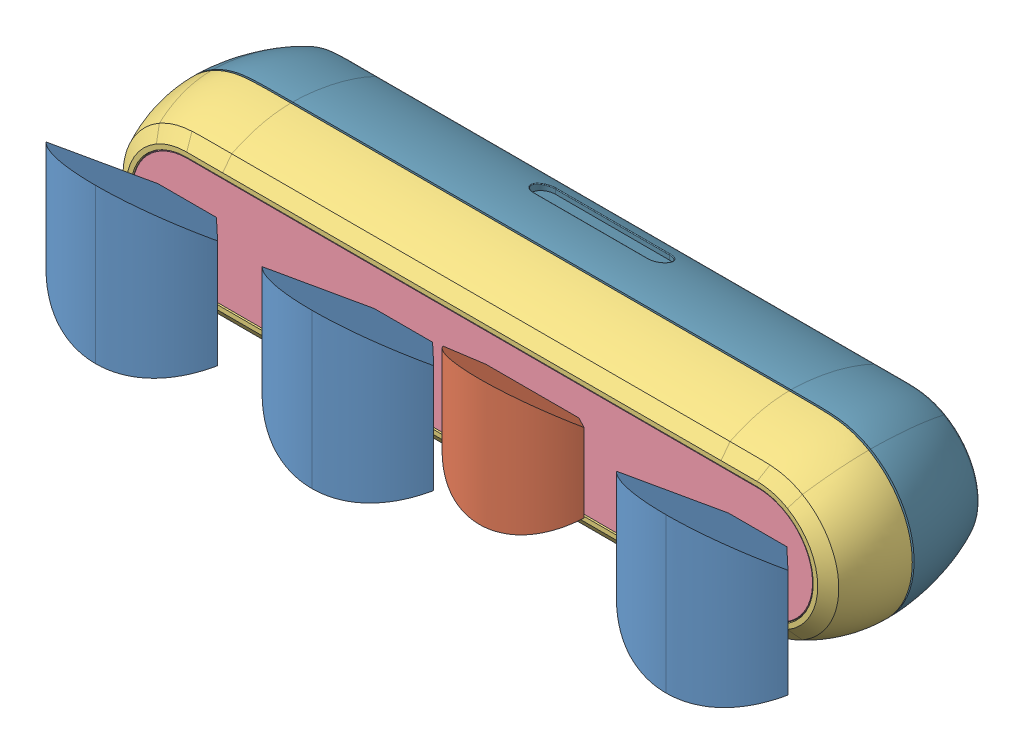
SolidWorks assembly Intel_RealSense_D455_CAD_external_v2, configuration Default. Lengths in mm.
Overall size (124.01 29.03 41.17).
49 component instances, 21 part files, 0 mates.
Components (placement in the parent):
- MD0645501_ASM_12_ASM-1: MD0645501_ASM_12_ASM [MD0645501_ASM_12_ASM] at origin size (124.01 29.03 26.02)
  - AM0600131_ASM_2_ASM-1: AM0600131_ASM_2_ASM [AM0600131_ASM_2_ASM] at origin size (124 29.01 12.31)
    - MEC060312_ASM_4_ASM-1: MEC060312_ASM_4_ASM [MEC060312_ASM_4_ASM] at origin size (111.1 18.8 0.79)
      - DS5_0390_FOAM_FRONT_D455_3-1: DS5_0390_FOAM_FRONT_D455_3 [DS5_0390_FOAM_FRONT_D455_3] at origin size (111.1 18.8 0.76)
      - DS5_0390_ADHESIVE_D455_2-1: DS5_0390_ADHESIVE_D455_2 [DS5_0390_ADHESIVE_D455_2] at (0 0 -1.32) size (111.1 18.8 0.03)
    - MEC060311_6-1: MEC060311_6 [MEC060311_6] at origin size (124 29.01 12.31)
  - AM0600132_ASM_3_ASM-1: AM0600132_ASM_3_ASM [AM0600132_ASM_3_ASM] at origin size (113.48 18.48 0.7)
    - MEC060313_2-1: MEC060313_2 [MEC060313_2] at origin size (113.48 18.48 0.55)
    - MASK_LENS_COVER_D455_3-1: MASK_LENS_COVER_D455_3 [MASK_LENS_COVER_D455_3] at origin size (113.28 18.28 0.03)
    - MEC060314_5-1: MEC060314_5 [MEC060314_5] at origin size (112.88 17.88 0.13)
  - AM0600135_ASM_3_ASM-1: AM0600135_ASM_3_ASM [AM0600135_ASM_3_ASM] at origin size (120.07 27.45 12.56)
    - MEC060318_11-1: MEC060318_11 [MEC060318_11] at origin size (120.07 27.45 12.56)
    - MEC060319_2-1: MEC060319_2 [MEC060319_2] at (35.3 0 -12.295) size (1.48 1.48 3)
    - MEC060319_2-2: MEC060319_2 [MEC060319_2] at (-38.5 0 -12.295) size (1.48 1.48 3)
  - MEC060309_ASM_5_ASM-1: MEC060309_ASM_5_ASM [MEC060309_ASM_5_ASM] at origin size (108.7 16.4 1.68)
    - DS5_0390_LABEL_FRONT_MOD_D455_5-1: DS5_0390_LABEL_FRONT_MOD_D455_5 [DS5_0390_LABEL_FRONT_MOD_D455_5] at origin size (108.7 16.4 1.68)
    - DS5_0390_LABEL_FRONT_ADH_D455_3-1: DS5_0390_LABEL_FRONT_ADH_D455_3 [DS5_0390_LABEL_FRONT_ADH_D455_3] at origin size (108.7 16.4 0.06)
  - AS0605401_ASM_4_ASM-1: AS0605401_ASM_4_ASM [AS0605401_ASM_4_ASM] at origin size (8.74 8.48 3.97)
    - 10137062C_1_ASM_2_ASM-1: 10137062C_1_ASM_2_ASM [10137062C_1_ASM_2_ASM] at (-37.01 -9 -21.3) x (1 0 0) z (0 -1 0) size (8.74 3.97 8.48)
      - 10137062C_1_1_1-1: 10137062C_1_1_1 [10137062C_1_1_1] at origin size (8.74 3.97 8.48)
  - AM0600133_ASM_2_ASM-1: AM0600133_ASM_2_ASM [AM0600133_ASM_2_ASM] at origin size (124.01 29.03 14.45)
    - FAS000227_ASM_2_ASM-1: FAS000227_ASM_2_ASM [FAS000227_ASM_2_ASM] at (-47.5 0 -25.4937) x (-1 0 0) z (0 1 0) size (5.62 3.92 5.68)
      - 91732A649_ASM_1_ASM-1: 91732A649_ASM_1_ASM [91732A649_ASM_1_ASM] at origin size (5.62 3.92 5.68)
        - SWEEP1_1-1: SWEEP1_1 [SWEEP1_1] at origin size (5.62 3.92 5.68)
    - FAS000227_ASM_2_ASM-2: FAS000227_ASM_2_ASM [FAS000227_ASM_2_ASM] at (47.5 0 -25.4937) x (-1 0 0) z (0 1 0) size (5.62 3.92 5.68)
      - 91732A649_ASM_1_ASM-1: 91732A649_ASM_1_ASM [91732A649_ASM_1_ASM] at origin size (5.62 3.92 5.68)
        - SWEEP1_1-1: SWEEP1_1 [SWEEP1_1] at origin size (5.62 3.92 5.68)
    - FAS000226_ASM_2_ASM-1: FAS000226_ASM_2_ASM [FAS000226_ASM_2_ASM] at (-44.51 -14.325 -19.85) size (2.7 1.95 2.7)
      - 91732A181_ASM_1_ASM-1: 91732A181_ASM_1_ASM [91732A181_ASM_1_ASM] at origin size (2.7 1.95 2.7)
        - SWEEP1_1_2_3_1-1: SWEEP1_1_2_3_1 [SWEEP1_1_2_3_1] at origin size (2.7 1.95 2.7)
    - FAS000226_ASM_2_ASM-2: FAS000226_ASM_2_ASM [FAS000226_ASM_2_ASM] at (-29.51 -14.325 -19.85) size (2.7 1.95 2.7)
      - 91732A181_ASM_1_ASM-1: 91732A181_ASM_1_ASM [91732A181_ASM_1_ASM] at origin size (2.7 1.95 2.7)
        - SWEEP1_1_2_3_1-1: SWEEP1_1_2_3_1 [SWEEP1_1_2_3_1] at origin size (2.7 1.95 2.7)
    - MEC060316_8-1: MEC060316_8 [MEC060316_8] at origin size (124.01 29.03 14.45)
    - MEC060019_1-1: MEC060019_1 [MEC060019_1] at (-2.4 9.5 -21.62) x (-1 0 0) z (0 1 0) size (1.6 1.6 1.6)
  - MEC060304_3-1: MEC060304_3 [MEC060304_3] at origin size (107.7 15.4 0.38)
  - FAS000225_6-1: FAS000225_6 [FAS000225_6] at (-58.25 0 -10.07) size (3.2 3.2 5.1)
  - FAS000225_6-2: FAS000225_6 [FAS000225_6] at (58.25 0 -10.07) size (3.2 3.2 5.1)
  - MEC060308_5-1: MEC060308_5 [MEC060308_5] at origin size (17.09 8.12 6.4)
- AM0600115_REV01_ASM_EXTERNA-517_ASM-1: AM0600115_REV01_ASM_EXTERNA-517_ASM [AM0600115_REV01_ASM_EXTERNA-517_ASM] at (11.3 0 -11.92) x (-1 0 0) z (0 0 -1) size (123.6 25.75 27.08)
  - AM0600115_REV01_ASM_EXTERNA-255_ASM-1: AM0600115_REV01_ASM_EXTERNA-255_ASM [AM0600115_REV01_ASM_EXTERNA-255_ASM] at origin size (123.6 25.75 21.32)
    - LEN000021_WITH_FOV_ASM_1_ASM_1__ASM-1: LEN000021_WITH_FOV_ASM_1_ASM_1__ASM [LEN000021_WITH_FOV_ASM_1_ASM_1__ASM] at (58.8 0 -0.82) x (-1 0 0) z (0 0 -1) size (28.6 25.75 19.81)
      - DS8480D-ASSM-MECH_00D1_OP_D6__1-1: DS8480D-ASSM-MECH_00D1_OP_D6__1 [DS8480D-ASSM-MECH_00D1_OP_D6__1] at (0 0 0.65) size (28.6 25.75 19.81)
    - LEN000021_WITH_FOV_ASM_1_ASM_1__ASM-2: LEN000021_WITH_FOV_ASM_1_ASM_1__ASM [LEN000021_WITH_FOV_ASM_1_ASM_1__ASM] at (-36.2 0 -0.82) x (-1 0 0) z (0 0 -1) size (28.6 25.75 19.81)
      - DS8480D-ASSM-MECH_00D1_OP_D6__1-1: DS8480D-ASSM-MECH_00D1_OP_D6__1 [DS8480D-ASSM-MECH_00D1_OP_D6__1] at (0 0 0.65) size (28.6 25.75 19.81)
    - LEN000021_WITH_FOV_ASM_1_ASM_1__ASM-3: LEN000021_WITH_FOV_ASM_1_ASM_1__ASM [LEN000021_WITH_FOV_ASM_1_ASM_1__ASM] at (22.8 0 -0.82) x (-1 0 0) z (0 0 -1) size (28.6 25.75 19.81)
      - DS8480D-ASSM-MECH_00D1_OP_D6__1-1: DS8480D-ASSM-MECH_00D1_OP_D6__1 [DS8480D-ASSM-MECH_00D1_OP_D6__1] at (0 0 0.65) size (28.6 25.75 19.81)
    - DS8580B-ASSM-MECH_02_OP_D6__FOV-1: DS8580B-ASSM-MECH_02_OP_D6__FOV [DS8580B-ASSM-MECH_02_OP_D6__FOV] at (1.3 0 -1.31) x (-1 0 0) z (0 0 -1) size (23.49 21.02 14.9)
  - AM0600115_INT_REV01_2_SW0001_1-1: AM0600115_INT_REV01_2_SW0001_1 [AM0600115_INT_REV01_2_SW0001_1] at origin size (119.5 17.41 10.5)
